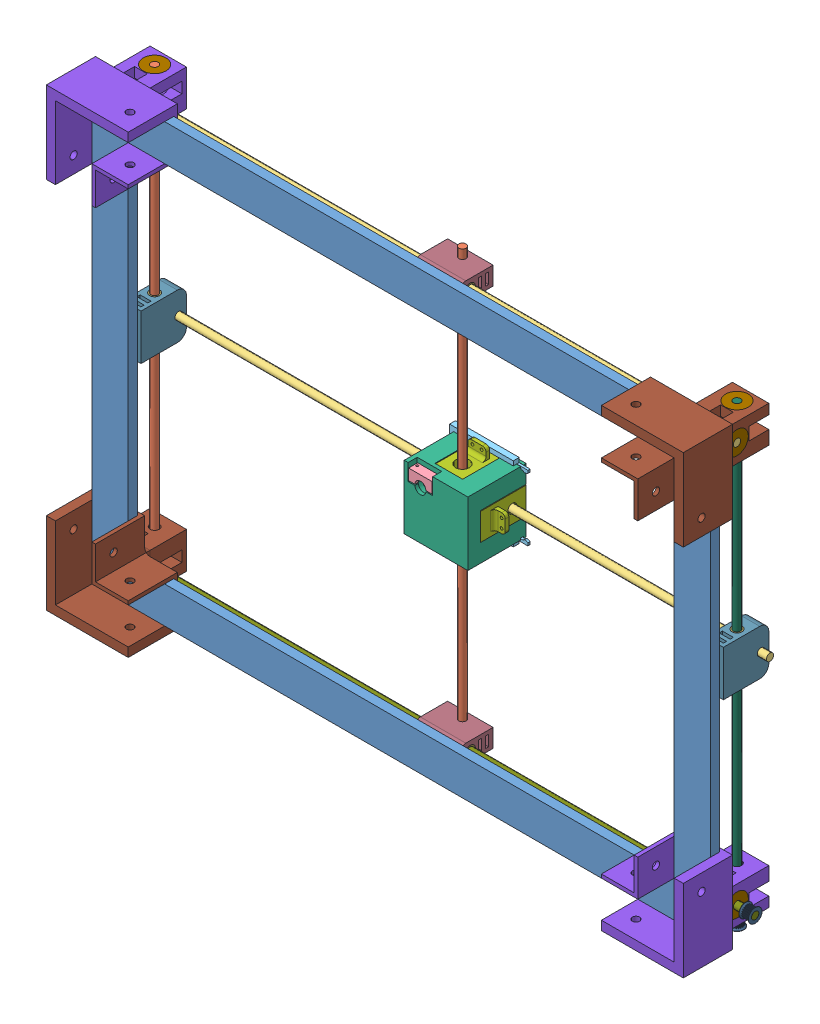
SolidWorks assembly Assemblage_XY, configuration Défaut. Lengths in mm.
Overall size (711.34 510 120.3).
50 component instances, 16 part files, 70 mates.
Components (placement in the parent):
- Cadre_XY-1: Cadre_XY [Défaut] at (379.0068 -247.2078 675) size (680 480 10)
- AXE_8X480-2: AXE_8X480 [Défaut] at (-280.9932 -247.2078 636) x (0.987721 0 0.156231) z (0 1 0) size (8 8 480)
- AXE_8X680-1: AXE_8X680 [Défaut] at (379.0068 212.7922 656) x (0 0.013067 0.999915) z (-1 0 0) size (8 8 680)
- AXE_8X480-3: AXE_8X480 [Défaut] at (60.9851 232.7922 639.7) x (0.999527 0 0.030742) z (0 -1 0) size (8 8 480)
- AXE_8X680-3: AXE_8X680 [Défaut] at (-300.9932 -9.5149 619.7) x (0 -0.696158 -0.717888) z (1 0 0) size (8 8 680)
- P3DMIPC-Tête_complete-1: P3DMIPC-Tête_complete [Défaut] at (16.7924 3.8551 635.2981) x (0 1 0) z (1 0 0) size (94 64.01 96.63)
  - P3DMIPC-Clip_Buse_E3D-1: P3DMIPC-Clip_Buse_E3D [Défaut] at (17.0518 23.4109 40.0035) x (1 0 0) z (0 1 0) size (12 26 10)
  - P3DMIPC-Clip_tête-1: P3DMIPC-Clip_tête [Défaut] at (26.9018 -25.0891 4.5597) x (1 0 0) z (0 -1 0) size (84 92 6.55)
  - P3DMIPC-Porte_Buse_E3DX1-1: P3DMIPC-Porte_Buse_E3DX1 [Défaut] at (22.03 33.4019 79.1927) x (0 0 1) z (0 -1 0) size (70 70 64)
  - P3DMIPC-Chariot-1: P3DMIPC-Chariot [Défaut] at (-48.37 -30.5981 79.1927) size (94 50 94)
- Angle_magique_G-1: Angle_magique_G [Défaut] at (379.0068 -247.2078 675) x (-1 0 0) z (0 0 -1) size (91.34 90 104)
- F608ZZ-1: F608ZZ [Défaut] at (372.0068 -227.2078 656) x (0 -0.924225 -0.381849) z (1 0 0) size (25 25 7)
- Angle_magique_G-4: Angle_magique_G [Défaut] at (-300.9932 232.7922 675) x (1 0 0) z (0 0 -1) size (91.34 90 104)
- pulley_gt2_3mm_20t-10: pulley_gt2_3mm_20t [Défaut] at (-280.9932 209.5422 636) x (0.106795 0 0.994281) z (0 1 0) size (15 15 10.5)
- pulley_gt2_3mm_20t-11: pulley_gt2_3mm_20t [Défaut] at (-277.7432 212.7922 656) x (0 0.106795 0.994281) z (-1 0 0) size (15 15 10.5)
- pulley_gt2_3mm_20t-12: pulley_gt2_3mm_20t [Défaut] at (-280.9932 -236.4578 636) x (-0.771074 0 0.636745) z (0 1 0) size (15 15 10.5)
- pulley_gt2_3mm_20t-13: pulley_gt2_3mm_20t [Défaut] at (-277.7432 -227.2078 656) x (0 0.106795 0.994281) z (-1 0 0) size (15 15 10.5)
- pulley_gt2_3mm_20t-15: pulley_gt2_3mm_20t [Défaut] at (359.0068 222.0422 636) x (-0.106795 0 0.994281) z (0 -1 0) size (15 15 10.5)
- pulley_gt2_3mm_20t-16: pulley_gt2_3mm_20t [Défaut] at (368.2568 212.7922 656) x (0 0.106795 0.994281) z (-1 0 0) size (15 15 10.5)
- F608ZZ-2: F608ZZ [Défaut] at (-280.9932 225.7922 636) x (-0.546944 0 0.837169) z (0 1 0) size (25 25 7)
- F608ZZ-3: F608ZZ [Défaut] at (-293.9932 212.7922 656) x (0 0 1) z (-1 0 0) size (25 25 7)
- F608ZZ-4: F608ZZ [Défaut] at (-293.9932 -227.2078 656) x (0 0 1) z (-1 0 0) size (25 25 7)
- F608ZZ-5: F608ZZ [Défaut] at (-280.9932 -240.2078 636) x (-0.924225 0 -0.381849) z (0 -1 0) size (25 25 7)
- F608ZZ-6: F608ZZ [Défaut] at (359.0068 -240.2078 636) x (-0.546944 0 0.837169) z (0 -1 0) size (25 25 7)
- F608ZZ-7: F608ZZ [Défaut] at (372.0068 212.7922 656) x (0 0 1) z (1 0 0) size (25 25 7)
- F608ZZ-8: F608ZZ [Défaut] at (359.0068 225.7922 636) x (0 0 1) z (0 1 0) size (25 25 7)
- Angle_magique_D-1: Angle_magique_D [Défaut] at (-300.9932 -247.2078 675) x (0 1 0) z (0 0 -1) size (90 91.34 104)
- Angle_magique_D-2: Angle_magique_D [Défaut] at (379.0068 232.7922 675) x (0 -1 0) z (0 0 -1) size (90 91.34 104)
- Assemblage_glissière_block_belt_palier_AR-1: Assemblage_glissière_block_belt_palier_AR [Défaut] at (181.51 -186.4667 609.4689) x (0 -1 0) z (-1 0 0) size (20 35 50)
  - ultimaker_cuivre_fritté_douille_8mmx11mmx22 mm-1: ultimaker_cuivre_fritté_douille_8mmx11mmx22 mm [Défaut] at (40.7411 46.5311 95.5249) size (11 11 22)
  - ultimaker_cuivre_fritté_douille_8mmx11mmx22 mm-2: ultimaker_cuivre_fritté_douille_8mmx11mmx22 mm [Défaut] at (40.7411 46.5311 123.5249) size (11 11 22)
  - Glisière_block_belt_AR-2: Glisière_block_belt_AR [Défaut] at (50.7411 14.5311 95.5249) size (20 35 50)
- Assemblage_glissière_block_belt_palier_AR-2: Assemblage_glissière_block_belt_palier_AR [Défaut] at (-59.5398 172.0511 609.4689) x (0 1 0) z (1 0 0) size (20 35 50)
  - ultimaker_cuivre_fritté_douille_8mmx11mmx22 mm-1: ultimaker_cuivre_fritté_douille_8mmx11mmx22 mm [Défaut] at (40.7411 46.5311 95.5249) size (11 11 22)
  - ultimaker_cuivre_fritté_douille_8mmx11mmx22 mm-2: ultimaker_cuivre_fritté_douille_8mmx11mmx22 mm [Défaut] at (40.7411 46.5311 123.5249) size (11 11 22)
  - Glisière_block_belt_AR-2: Glisière_block_belt_AR [Défaut] at (50.7411 14.5311 95.5249) size (20 35 50)
- pulley_gt2_3mm_20t-17: pulley_gt2_3mm_20t [Défaut] at (368.2568 -227.2078 656) x (0 0.106795 0.994281) z (-1 0 0) size (15 15 10.5)
- pulley_gt2_3mm_20t-18: pulley_gt2_3mm_20t [Défaut] at (359.0068 -223.9578 636) x (0.203502 0 0.979074) z (0 -1 0) size (15 15 10.5)
- Assemblage_glissière_block_belt_palier_GD-1: Assemblage_glissière_block_belt_palier_GD [Défaut] at (364.4936 -84.5149 631.6132) x (-1 0 0) z (0 1 0) size (20 50 50)
  - Glisière_block_belt_GD-1: Glisière_block_belt_GD [Défaut] at (15.4869 -20.6132 50) size (20 50 50)
  - ultimaker_cuivre_fritté_douille_8mmx11mmx22 mm-1: ultimaker_cuivre_fritté_douille_8mmx11mmx22 mm [Défaut] at (5.4869 4.3868 50) size (11 11 22)
  - ultimaker_cuivre_fritté_douille_8mmx11mmx22 mm-2: ultimaker_cuivre_fritté_douille_8mmx11mmx22 mm [Défaut] at (5.4869 4.3868 78) size (11 11 22)
- Assemblage_glissière_block_belt_palier_GD-2: Assemblage_glissière_block_belt_palier_GD [Défaut] at (-286.4801 65.4851 631.6132) x (1 0 0) z (0 -1 0) size (20 50 50)
  - Glisière_block_belt_GD-1: Glisière_block_belt_GD [Défaut] at (15.4869 -20.6132 50) size (20 50 50)
  - ultimaker_cuivre_fritté_douille_8mmx11mmx22 mm-1: ultimaker_cuivre_fritté_douille_8mmx11mmx22 mm [Défaut] at (5.4869 4.3868 50) size (11 11 22)
  - ultimaker_cuivre_fritté_douille_8mmx11mmx22 mm-2: ultimaker_cuivre_fritté_douille_8mmx11mmx22 mm [Défaut] at (5.4869 4.3868 78) size (11 11 22)
- AXE_8X500_Moteur-1: AXE_8X500_Moteur [Défaut] at (359.0068 -267.2078 636) x (0.283264 0 -0.959042) z (0 1 0) size (8 8 500)
- AXE_8X700_Moteur-1: AXE_8X700_Moteur [Défaut] at (399.0068 -227.2078 656) x (0 0 1) z (-1 0 0) size (8 8 700)
- pulley_gt2_3mm_20t-19: pulley_gt2_3mm_20t [Défaut] at (359.0068 -255.7078 636) x (0.203502 0 0.979074) z (0 -1 0) size (15 15 10.5)
- pulley_gt2_3mm_20t-20: pulley_gt2_3mm_20t [Défaut] at (387.5068 -227.2078 656) x (0 0.203502 0.979074) z (1 0 0) size (15 15 10.5)
Mates (geometry in assembly coordinates):
- Coaxiale1: concentric anti-aligned: cylinder of AXE_8X680-3 through (379.0068 -9.5149 619.7) axis (-1 0 0) radius 4; cylinder of P3DMIPC-Tête_complete-1/P3DMIPC-Chariot-1 through (91.9851 -9.5149 619.7) axis (1 0 0) radius 5
- Coaxiale2: concentric anti-aligned: cylinder of AXE_8X480-3 through (60.9851 -247.2078 639.7) axis (0 1 0) radius 4; cylinder of P3DMIPC-Tête_complete-1/P3DMIPC-Chariot-1 through (60.9851 -40.5149 639.7) axis (0 -1 0) radius 5
- Coïncidente14: coincident anti-aligned: plane of Cadre_XY-1 through (379.0068 -247.2078 675) normal (0 0 -1); plane of Angle_magique_G-1 through (379.0068 -247.2078 675) normal (0 0 1)
- Coïncidente15: coincident anti-aligned: plane of Cadre_XY-1 through (379.0068 -247.2078 685) normal (1 0 0); plane of Angle_magique_G-1 through (379.0068 -247.2078 725) normal (-1 0 0)
- Coïncidente16: coincident anti-aligned: plane of Cadre_XY-1 through (379.0068 -247.2078 685) normal (0 -1 0); plane of Angle_magique_G-1 through (299.0068 -247.2078 725) normal (0 1 0)
- Coïncidente27: coincident anti-aligned: plane of Cadre_XY-1 through (379.0068 -247.2078 675) normal (0 0 -1); plane of Angle_magique_G-4 through (-300.9932 232.7922 675) normal (0 0 1)
- Coïncidente28: coincident anti-aligned: plane of Cadre_XY-1 through (379.0068 232.7922 685) normal (0 1 0); plane of Angle_magique_G-4 through (-220.9932 232.7922 725) normal (0 -1 0)
- Coïncidente29: coincident anti-aligned: plane of Cadre_XY-1 through (-300.9932 -247.2078 685) normal (-1 0 0); plane of Angle_magique_G-4 through (-300.9932 232.7922 725) normal (1 0 0)
- Coaxiale17: concentric anti-aligned: cylinder of AXE_8X680-1 through (-300.9932 212.7922 656) axis (1 0 0) radius 4; cylinder of pulley_gt2_3mm_20t-11 through (-277.7432 212.7922 656) axis (-1 0 0) radius 4
- Coaxiale18: concentric aligned: cylinder of AXE_8X680-1 through (-300.9932 212.7922 656) axis (1 0 0) radius 4; cylinder of Angle_magique_G-4 through (-310.9932 212.7922 656) axis (1 0 0) radius 5
- Coïncidente30: coincident aligned: plane of Cadre_XY-1 through (-300.9932 -247.2078 685) normal (-1 0 0); plane of AXE_8X680-1 through (-300.9932 212.7922 656) normal (-1 0 0)
- Distance2: distance = 2.75 mm anti-aligned: plane of pulley_gt2_3mm_20t-11 through (-278.7432 212.7922 656) normal (1 0 0); plane of Angle_magique_G-4 through (-275.9932 192.7922 621) normal (-1 0 0)
- Coaxiale19: concentric anti-aligned: cylinder of AXE_8X680-1 through (-300.9932 212.7922 656) axis (1 0 0) radius 4; cylinder of pulley_gt2_3mm_20t-16 through (368.2568 212.7922 656) axis (-1 0 0) radius 4
- Coaxiale24: concentric aligned: cylinder of AXE_8X480-2 through (-280.9932 232.7922 636) axis (0 -1 0) radius 4; cylinder of Angle_magique_G-4 through (-280.9932 232.7923 636) axis (0 -1 0) radius 5
- Coaxiale25: concentric anti-aligned: cylinder of AXE_8X480-2 through (-280.9932 232.7922 636) axis (0 -1 0) radius 4; cylinder of pulley_gt2_3mm_20t-10 through (-280.9932 209.5422 636) axis (0 1 0) radius 4
- Coïncidente34: coincident aligned: plane of Cadre_XY-1 through (379.0068 232.7922 685) normal (0 1 0); plane of AXE_8X480-2 through (-280.9932 232.7922 636) normal (0 1 0)
- Distance4: distance = 2.75 mm anti-aligned: plane of pulley_gt2_3mm_20t-10 through (-280.9932 210.5422 636) normal (0 -1 0); plane of Angle_magique_G-4 through (-275.9932 207.7922 621) normal (0 1 0)
- Coaxiale26: concentric anti-aligned: cylinder of AXE_8X480-2 through (-280.9932 232.7922 636) axis (0 -1 0) radius 4; cylinder of pulley_gt2_3mm_20t-12 through (-280.9932 -236.4578 636) axis (0 1 0) radius 4
- Coïncidente44: coincident anti-aligned: plane of Cadre_XY-1 through (379.0068 -247.2078 675) normal (0 0 -1); plane of Angle_magique_D-1 through (-300.9932 -247.2078 675) normal (0 0 1)
- Coïncidente45: coincident anti-aligned: plane of Cadre_XY-1 through (379.0068 -247.2078 685) normal (0 -1 0); plane of Angle_magique_D-1 through (-300.9932 -247.2078 725) normal (0 1 0)
- Coïncidente46: coincident anti-aligned: plane of Cadre_XY-1 through (-300.9932 -247.2078 685) normal (-1 0 0); plane of Angle_magique_D-1 through (-300.9932 -167.2078 725) normal (1 0 0)
- Distance10: distance = 2.75 mm anti-aligned: plane of Angle_magique_D-1 through (-260.9932 -222.2078 621) normal (0 -1 0); plane of pulley_gt2_3mm_20t-12 through (-280.9932 -224.9578 636) normal (0 1 0)
- Coïncidente51: coincident anti-aligned: plane of Cadre_XY-1 through (379.0068 -247.2078 675) normal (0 0 -1); plane of Angle_magique_D-2 through (379.0068 232.7922 675) normal (0 0 1)
- Coïncidente52: coincident anti-aligned: plane of Cadre_XY-1 through (379.0068 232.7922 685) normal (0 1 0); plane of Angle_magique_D-2 through (379.0068 232.7922 725) normal (0 -1 0)
- Coïncidente53: coincident anti-aligned: plane of Cadre_XY-1 through (379.0068 -247.2078 685) normal (1 0 0); plane of Angle_magique_D-2 through (379.0068 152.7922 725) normal (-1 0 0)
- Distance11: distance = 2.75 mm anti-aligned: plane of pulley_gt2_3mm_20t-15 through (359.0068 210.5422 636) normal (0 -1 0); plane of Angle_magique_D-2 through (339.0068 207.7922 621) normal (0 1 0)
- Distance12: distance = 2.75 mm anti-aligned: plane of Angle_magique_D-2 through (354.0068 207.7922 621) normal (1 0 0); plane of pulley_gt2_3mm_20t-16 through (356.7568 212.7922 656) normal (-1 0 0)
- Coaxiale39: concentric anti-aligned: cylinder of AXE_8X680-1 through (-300.9932 212.7922 656) axis (1 0 0) radius 4; cylinder of Assemblage_glissière_block_belt_palier_AR-2/ultimaker_cuivre_fritté_douille_8mmx11mmx22 mm-1 through (57.9851 212.7922 656) axis (-1 0 0) radius 4
- Coaxiale42: concentric anti-aligned: cylinder of AXE_8X480-3 through (60.9851 -247.2078 639.7) axis (0 1 0) radius 4; cylinder of Assemblage_glissière_block_belt_palier_AR-2/Glisière_block_belt_AR-2 through (60.9851 222.7922 639.7) axis (0 -1 0) radius 4
- Coaxiale43: concentric aligned: cylinder of AXE_8X480-3 through (60.9851 -247.2078 639.7) axis (0 1 0) radius 4; cylinder of Assemblage_glissière_block_belt_palier_AR-1/Glisière_block_belt_AR-2 through (60.9851 -237.2078 639.7) axis (0 1 0) radius 4
- Coaxiale50: concentric anti-aligned: cylinder of F608ZZ-7 through (377.5068 212.7922 656) axis (-1 0 0) radius 11; cylinder of Angle_magique_D-2 through (372.0068 212.7922 656) axis (1 0 0) radius 11
- Coïncidente63: coincident anti-aligned: plane of F608ZZ-7 through (372.0068 212.7922 656) normal (-1 0 0); plane of Angle_magique_D-2 through (372.0068 212.7922 656) normal (1 0 0)
- Coaxiale51: concentric anti-aligned: cylinder of F608ZZ-8 through (359.0068 231.2922 636) axis (0 -1 0) radius 11; cylinder of Angle_magique_D-2 through (359.0068 225.7922 636) axis (0 1 0) radius 11
- Coïncidente64: coincident anti-aligned: plane of F608ZZ-8 through (359.0068 225.7922 636) normal (0 -1 0); plane of Angle_magique_D-2 through (359.0068 225.7922 636) normal (0 1 0)
- Coïncidente65: coincident anti-aligned: plane of Angle_magique_G-4 through (-280.9932 225.7922 636) normal (0 1 0); plane of F608ZZ-2 through (-280.9932 225.7922 636) normal (0 -1 0)
- Coaxiale53: concentric anti-aligned: cylinder of Angle_magique_G-4 through (-280.9932 225.7922 636) axis (0 1 0) radius 11; cylinder of F608ZZ-2 through (-280.9932 231.2922 636) axis (0 -1 0) radius 11
- Coaxiale54: concentric anti-aligned: cylinder of Angle_magique_G-4 through (-293.9932 212.7922 656) axis (-1 0 0) radius 11; cylinder of F608ZZ-3 through (-299.4932 212.7922 656) axis (1 0 0) radius 11
- Coïncidente66: coincident anti-aligned: plane of Angle_magique_G-4 through (-293.9932 212.7922 656) normal (-1 0 0); plane of F608ZZ-3 through (-293.9932 212.7922 656) normal (1 0 0)
- Coaxiale57: concentric anti-aligned: cylinder of F608ZZ-4 through (-299.4932 -227.2078 656) axis (1 0 0) radius 11; cylinder of Angle_magique_D-1 through (-293.9932 -227.2078 656) axis (-1 0 0) radius 11
- Coïncidente69: coincident anti-aligned: plane of F608ZZ-4 through (-293.9932 -227.2078 656) normal (1 0 0); plane of Angle_magique_D-1 through (-293.9932 -227.2078 656) normal (-1 0 0)
- Coïncidente70: coincident anti-aligned: plane of F608ZZ-5 through (-280.9932 -240.2078 636) normal (0 1 0); plane of Angle_magique_D-1 through (-280.9932 -240.2078 636) normal (0 -1 0)
- Coaxiale58: concentric anti-aligned: cylinder of F608ZZ-5 through (-280.9932 -245.7078 636) axis (0 1 0) radius 11; cylinder of Angle_magique_D-1 through (-280.9932 -240.2078 636) axis (0 -1 0) radius 11
- Distance14: distance = 2.75 mm anti-aligned: plane of Angle_magique_G-1 through (354.0068 -222.2078 621) normal (0 -1 0); plane of pulley_gt2_3mm_20t-18 through (359.0068 -224.9578 636) normal (0 1 0)
- Distance15: distance = 2.75 mm anti-aligned: plane of Angle_magique_G-1 through (354.0068 -207.2078 621) normal (1 0 0); plane of pulley_gt2_3mm_20t-17 through (356.7568 -227.2078 656) normal (-1 0 0)
- Coïncidente73: coincident anti-aligned: plane of Angle_magique_G-1 through (359.0068 -240.2078 636) normal (0 -1 0); plane of F608ZZ-6 through (359.0068 -240.2078 636) normal (0 1 0)
- Coaxiale61: concentric anti-aligned: cylinder of Angle_magique_G-1 through (359.0068 -240.2078 636) axis (0 -1 0) radius 11; cylinder of F608ZZ-6 through (359.0068 -245.7078 636) axis (0 1 0) radius 11
- Coïncidente74: coincident anti-aligned: plane of Angle_magique_G-1 through (372.0068 -227.2078 656) normal (1 0 0); plane of F608ZZ-1 through (372.0068 -227.2078 656) normal (-1 0 0)
- Coaxiale62: concentric anti-aligned: cylinder of Angle_magique_G-1 through (372.0068 -227.2078 656) axis (1 0 0) radius 11; cylinder of F608ZZ-1 through (377.5068 -227.2078 656) axis (-1 0 0) radius 11
- Coaxiale64: concentric anti-aligned: cylinder of AXE_8X680-3 through (379.0068 -9.5149 619.7) axis (-1 0 0) radius 4; cylinder of Assemblage_glissière_block_belt_palier_GD-1/Glisière_block_belt_GD-1 through (349.0068 -9.5149 619.7) axis (1 0 0) radius 4
- Coaxiale65: concentric anti-aligned: cylinder of Assemblage_glissière_block_belt_palier_GD-2/ultimaker_cuivre_fritté_douille_8mmx11mmx22 mm-1 through (-280.9932 -6.5149 636) axis (0 1 0) radius 4; cylinder of AXE_8X480-2 through (-280.9932 232.7922 636) axis (0 -1 0) radius 4
- Coaxiale66: concentric aligned: cylinder of AXE_8X680-3 through (379.0068 -9.5149 619.7) axis (-1 0 0) radius 4; cylinder of Assemblage_glissière_block_belt_palier_GD-2/Glisière_block_belt_GD-1 through (-270.9932 -9.5149 619.7) axis (-1 0 0) radius 4
- Coïncidente75: coincident aligned: plane of Cadre_XY-1 through (-300.9932 -247.2078 685) normal (-1 0 0); plane of AXE_8X680-3 through (-300.9932 -9.5149 619.7) normal (-1 0 0)
- Coïncidente76: coincident aligned: plane of Cadre_XY-1 through (379.0068 -247.2078 685) normal (0 -1 0); plane of AXE_8X480-3 through (60.9851 -247.2078 639.7) normal (0 -1 0)
- Distance17: distance = 2.75 mm anti-aligned: plane of pulley_gt2_3mm_20t-13 through (-278.7432 -227.2078 656) normal (1 0 0); plane of Angle_magique_D-1 through (-275.9932 -222.2078 621) normal (-1 0 0)
- Coaxiale67: concentric anti-aligned: cylinder of Angle_magique_G-1 through (389.0068 -227.2078 656) axis (-1 0 0) radius 5; cylinder of AXE_8X700_Moteur-1 through (-300.9932 -227.2078 656) axis (1 0 0) radius 4
- Coaxiale68: concentric aligned: cylinder of Assemblage_glissière_block_belt_palier_AR-1/ultimaker_cuivre_fritté_douille_8mmx11mmx22 mm-2 through (35.9851 -227.2078 656) axis (1 0 0) radius 4; cylinder of AXE_8X700_Moteur-1 through (-300.9932 -227.2078 656) axis (1 0 0) radius 4
- Coaxiale69: concentric aligned: cylinder of Angle_magique_D-1 through (-310.9932 -227.2078 656) axis (1 0 0) radius 5; cylinder of AXE_8X700_Moteur-1 through (-300.9932 -227.2078 656) axis (1 0 0) radius 4
- Coïncidente80: coincident aligned: plane of Cadre_XY-1 through (-300.9932 -247.2078 685) normal (-1 0 0); plane of AXE_8X700_Moteur-1 through (-300.9932 -227.2078 656) normal (-1 0 0)
- Coaxiale70: concentric anti-aligned: cylinder of pulley_gt2_3mm_20t-13 through (-277.7432 -227.2078 656) axis (-1 0 0) radius 4; cylinder of AXE_8X700_Moteur-1 through (-300.9932 -227.2078 656) axis (1 0 0) radius 4
- Coaxiale71: concentric anti-aligned: cylinder of pulley_gt2_3mm_20t-17 through (368.2568 -227.2078 656) axis (-1 0 0) radius 4; cylinder of AXE_8X700_Moteur-1 through (-300.9932 -227.2078 656) axis (1 0 0) radius 4
- Coaxiale72: concentric aligned: cylinder of Assemblage_glissière_block_belt_palier_GD-1/ultimaker_cuivre_fritté_douille_8mmx11mmx22 mm-2 through (359.0068 15.4851 636) axis (0 -1 0) radius 4; cylinder of AXE_8X500_Moteur-1 through (359.0068 232.7922 636) axis (0 -1 0) radius 4
- Coaxiale73: concentric anti-aligned: cylinder of Angle_magique_G-1 through (359.0068 -247.2078 636) axis (0 1 0) radius 5; cylinder of AXE_8X500_Moteur-1 through (359.0068 232.7922 636) axis (0 -1 0) radius 4
- Coaxiale74: concentric aligned: cylinder of Angle_magique_D-2 through (359.0068 242.7922 636) axis (0 -1 0) radius 5; cylinder of AXE_8X500_Moteur-1 through (359.0068 232.7922 636) axis (0 -1 0) radius 4
- Coaxiale75: concentric aligned: cylinder of pulley_gt2_3mm_20t-15 through (359.0068 222.0422 636) axis (0 -1 0) radius 4; cylinder of AXE_8X500_Moteur-1 through (359.0068 232.7922 636) axis (0 -1 0) radius 4
- Coaxiale76: concentric aligned: cylinder of pulley_gt2_3mm_20t-18 through (359.0068 -223.9578 636) axis (0 -1 0) radius 4; cylinder of AXE_8X500_Moteur-1 through (359.0068 232.7922 636) axis (0 -1 0) radius 4
- Coïncidente81: coincident aligned: plane of Cadre_XY-1 through (379.0068 232.7922 685) normal (0 1 0); plane of AXE_8X500_Moteur-1 through (359.0068 232.7922 636) normal (0 1 0)
- Coaxiale77: concentric aligned: cylinder of AXE_8X500_Moteur-1 through (359.0068 232.7922 636) axis (0 -1 0) radius 4; cylinder of pulley_gt2_3mm_20t-19 through (359.0068 -255.7078 636) axis (0 -1 0) radius 4
- Coïncidente82: coincident aligned: plane of AXE_8X500_Moteur-1 through (359.0068 -267.2078 636) normal (0 -1 0); plane of pulley_gt2_3mm_20t-19 through (359.0068 -267.2078 636) normal (0 -1 0)
- Coïncidente83: coincident aligned: plane of AXE_8X700_Moteur-1 through (399.0068 -227.2078 656) normal (1 0 0); plane of pulley_gt2_3mm_20t-20 through (399.0068 -227.2078 656) normal (1 0 0)
- Coaxiale78: concentric aligned: cylinder of AXE_8X700_Moteur-1 through (-300.9932 -227.2078 656) axis (1 0 0) radius 4; cylinder of pulley_gt2_3mm_20t-20 through (387.5068 -227.2078 656) axis (1 0 0) radius 4
